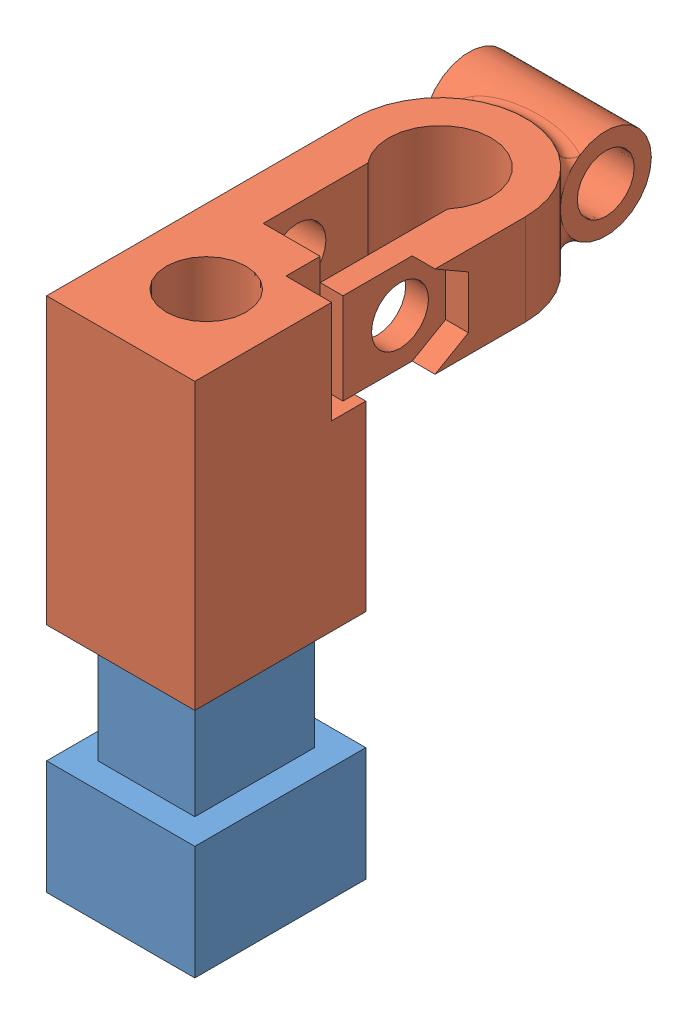
SolidWorks assembly Assem1, configuration Default. Lengths in mm.
Overall size (15 45.33 41.05).
2 component instances, 2 part files, 2 mates.
Components (placement in the parent):
- button_holder_z_axis_aux-1: button_holder_z_axis_aux [Default] at (-1.4254 -2.3041 25.9757) size (13 32 15)
- button_holder_z_axis-1: button_holder_z_axis [Default] at (-1.4254 35.0217 12.9757) size (15 25 41.05)
Mates (geometry in assembly coordinates):
- Concentric1: concentric aligned: cylinder of button_holder_z_axis_aux-1 through (5.0746 27.6959 18.4757) axis (0 1 0) radius 2.25; cylinder of button_holder_z_axis-1 through (5.0746 36.0217 18.4757) axis (0 1 0) radius 3.5
- Coincident1: coincident aligned: plane of button_holder_z_axis_aux-1 through (-1.4254 7.6959 25.9757) normal (0 0 1); plane of button_holder_z_axis-1 through (-1.4254 18.0217 25.9757) normal (0 0 1)
